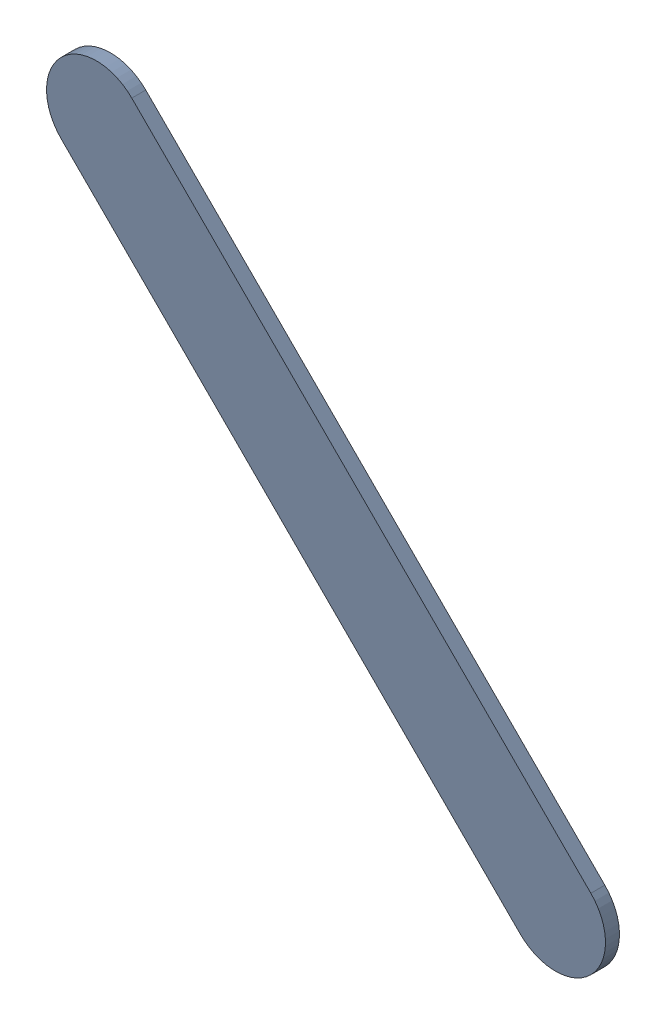
SolidWorks assembly Track (18.034mm,45.033mm)(19.202mm,43.865mm) on Bottom Layer, configuration Predeterminado. Lengths in mm.
Overall size (1.42 1.42 0.04).
2 component instances, 1 part files, 0 mates.
Components (placement in the parent):
- Track (18.034mm,45.033mm)(19.202mm,43.865mm) on Bottom Layer-1-1: Track (18.034mm,45.033mm)(19.202mm,43.865mm) on Bottom Layer-1 [Predeterminado] at (-68.317 -44.187 -0.4013) size (1.42 1.42 0.04)
  - Track (18.034mm,45.033mm)(19.202mm,43.865mm) on Bottom Layer-Part-1-1: Track (18.034mm,45.033mm)(19.202mm,43.865mm) on Bottom Layer-Part-1 [Predeterminado] at origin size (1.42 1.42 0.04)
